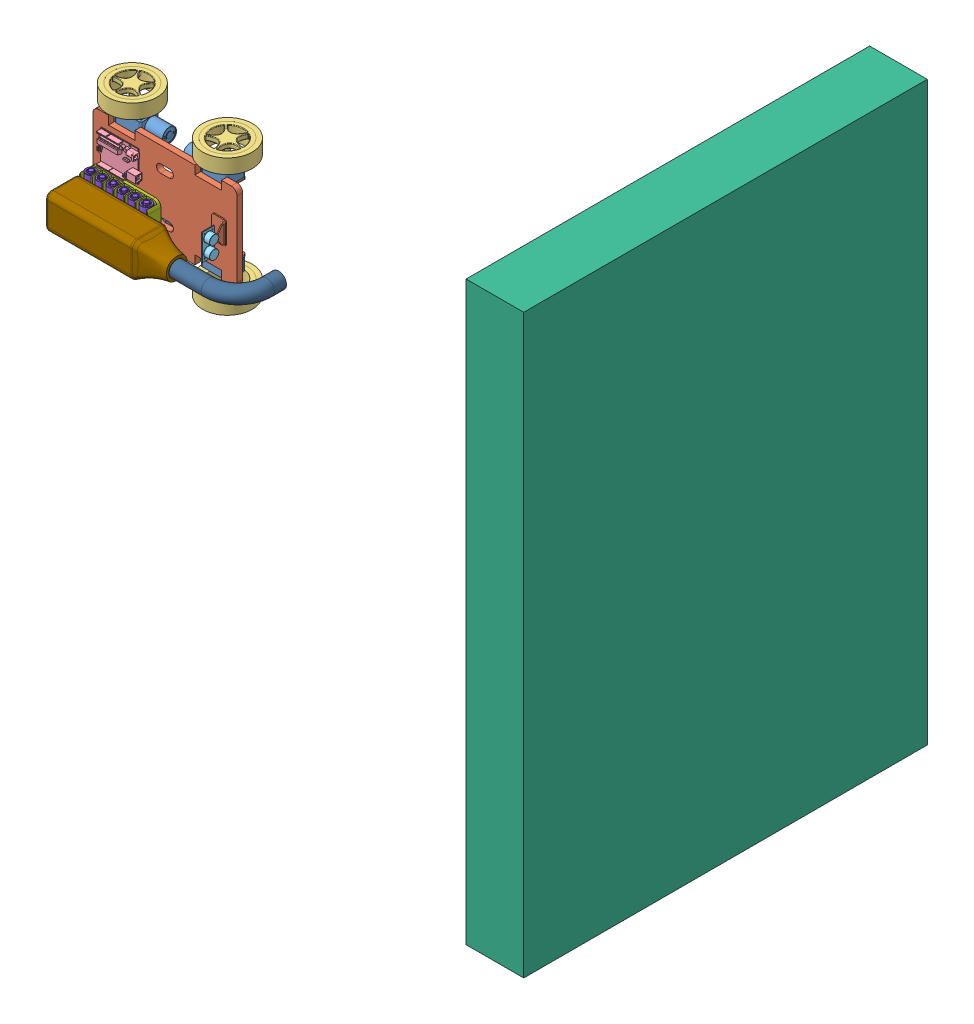
SolidWorks assembly Assem, configuration Default. Lengths in mm.
Overall size (1079.66 1000 700).
22 component instances, 10 part files, 36 mates.
Components (placement in the parent):
- 12v_DC_Gearmotor-1: 12v_DC_Gearmotor [Default] at (-163.6493 278.5619 69.9489) x (-1 0 0) z (0 0 1) size (79 38.4 32)
- Rover base-1: Rover base [Default] at (-238.6033 338.5619 90.9489) x (-1 0 0) z (0 0 1) size (250 150 80.5)
- 12v_DC_Gearmotor-2: 12v_DC_Gearmotor [Default] at (-163.6493 398.5619 69.9489) x (-1 0 0) z (0 0 -1) size (79 38.4 32)
- 12v_DC_Gearmotor-3: 12v_DC_Gearmotor [Default] at (-313.5573 278.5619 69.9489) x (1 0 0) z (0 0 -1) size (79 38.4 32)
- 12v_DC_Gearmotor-4: 12v_DC_Gearmotor [Default] at (-313.5573 398.5619 69.9489) size (79 38.4 32)
- Rover Tire-1: Rover Tire [Default] at (-321.0573 232.8619 69.9489) size (86 33.19 86)
- Rover Tire-3: Rover Tire [Default] at (-156.1493 232.8619 69.9489) size (86 33.19 86)
- Rover Tire-4: Rover Tire [Default] at (-156.1493 444.2619 69.9489) x (-0.973958 0 -0.22673) z (-0.22673 0 0.973958) size (86 33.19 86)
- Rover Tire-5: Rover Tire [Default] at (-321.0573 444.2619 69.9489) x (-0.837169 0 -0.546944) z (-0.546944 0 0.837169) size (86 33.19 86)
- arduino uno-1: arduino uno [Predeterminado] at (-316.1033 363.0619 95.9489) x (1 0 0) z (0 -1 0) size (74 12.5 53)
- ultrasonic sensor-1: ultrasonic sensor [Default] at (-131.8533 338.5619 127.9489) x (0 1 0) z (1 0 0) size (45.2 21 11.5)
- Wall-1: Wall [Default] at (649.0852 292.811 61.2372) x (0 0 1) z (-1 0 0) size (700 1000 100)
- Assem2-1: Assem2 [Default] at (-320.9073 237.9966 6.8256) size (118 67 23.02)
  - Battery Holder-1: Battery Holder [Default] at (16.304 59.0653 91.6233) size (118 67 23)
  - Lithium ion battery-1: Lithium ion battery [Default] at (-31.6544 58.0653 103.1233) size (18 66.5 18.02)
  - Lithium ion battery-2: Lithium ion battery [Default] at (64.3357 58.0653 103.1233) size (18 66.5 18.02)
  - Lithium ion battery-3: Lithium ion battery [Default] at (25.9042 58.0653 103.1233) size (18 66.5 18.02)
  - Lithium ion battery-4: Lithium ion battery [Default] at (6.6883 58.0653 103.1233) size (18 66.5 18.02)
  - Lithium ion battery-5: Lithium ion battery [Default] at (44.6923 58.0653 103.1233) size (18 66.5 18.02)
  - Lithium ion battery-6: Lithium ion battery [Default] at (-12.2228 58.0653 103.1233) size (18 66.5 18.02)
- vacuum bottle-1: vacuum bottle [Default] at (-288.6033 295.5619 148.9489) x (0 0 -1) z (1 0 0) size (60 60 218.62)
- vaccpipe-1: vaccpipe [Default] at (-164.9833 295.5619 148.9489) x (1 0 0) z (0 -1 0) size (119.32 84.35 27)
Mates (geometry in assembly coordinates):
- Coincident18: coincident anti-aligned: plane of 12v_DC_Gearmotor-1 through (-163.6493 278.5619 69.9489) normal (0 1 0); plane of Rover base-1 through (-140.6493 278.5619 85.9489) normal (0 -1 0)
- Coincident16: coincident anti-aligned: plane of 12v_DC_Gearmotor-1 through (-140.6493 257.0619 85.9489) normal (0 0 1); plane of Rover base-1 through (-238.6033 338.5619 85.9489) normal (0 0 -1)
- Coincident17: coincident aligned: plane of 12v_DC_Gearmotor-1 through (-140.6493 257.0619 85.9489) normal (1 0 0); plane of Rover base-1 through (-140.6493 283.5619 53.9489) normal (1 0 0)
- Coincident19: coincident aligned: plane of Rover base-1 through (-140.6493 393.5619 53.9489) normal (1 0 0); plane of 12v_DC_Gearmotor-2 through (-140.6493 420.0619 53.9489) normal (1 0 0)
- Coincident20: coincident anti-aligned: plane of Rover base-1 through (-140.6493 398.5619 85.9489) normal (0 1 0); plane of 12v_DC_Gearmotor-2 through (-163.6493 398.5619 69.9489) normal (0 -1 0)
- Coincident21: coincident anti-aligned: plane of Rover base-1 through (-238.6033 338.5619 85.9489) normal (0 0 -1); plane of 12v_DC_Gearmotor-2 through (-140.6493 420.0619 85.9489) normal (0 0 1)
- Coincident25: coincident anti-aligned: plane of Rover base-1 through (-336.5573 398.5619 85.9489) normal (0 1 0); plane of 12v_DC_Gearmotor-4 through (-313.5573 398.5619 69.9489) normal (0 -1 0)
- Coincident26: coincident aligned: plane of Rover base-1 through (-336.5573 393.5619 53.9489) normal (-1 0 0); plane of 12v_DC_Gearmotor-4 through (-336.5573 420.0619 85.9489) normal (-1 0 0)
- Coincident27: coincident anti-aligned: plane of Rover base-1 through (-238.6033 338.5619 85.9489) normal (0 0 -1); plane of 12v_DC_Gearmotor-4 through (-336.5573 420.0619 85.9489) normal (0 0 1)
- Coincident28: coincident anti-aligned: plane of Rover base-1 through (-336.5573 278.5619 85.9489) normal (0 -1 0); plane of 12v_DC_Gearmotor-3 through (-313.5573 278.5619 69.9489) normal (0 1 0)
- Coincident29: coincident aligned: plane of Rover base-1 through (-336.5573 283.5619 53.9489) normal (-1 0 0); plane of 12v_DC_Gearmotor-3 through (-336.5573 257.0619 53.9489) normal (-1 0 0)
- Coincident30: coincident anti-aligned: plane of Rover base-1 through (-238.6033 338.5619 85.9489) normal (0 0 -1); plane of 12v_DC_Gearmotor-3 through (-336.5573 257.0619 85.9489) normal (0 0 1)
- Concentric11: concentric aligned: line of 12v_DC_Gearmotor-4 through (-321.0573 433.7619 69.9489) axis (0 -1 0); cylinder of Rover Tire-5 through (-321.0573 433.7619 69.9489) axis (0 -1 0) radius 2.5
- Coincident31: coincident anti-aligned: plane of 12v_DC_Gearmotor-4 through (-321.0573 433.7619 69.9489) normal (0 1 0); plane of Rover Tire-5 through (-321.0573 433.7619 69.9489) normal (0 -1 0)
- Concentric2: concentric aligned: cylinder of 12v_DC_Gearmotor-2 through (-156.1493 433.7619 69.9489) axis (0 -1 0) radius 3; cylinder of Rover Tire-4 through (-156.1493 433.7619 69.9489) axis (0 -1 0) radius 2.5
- Coincident33: coincident anti-aligned: plane of 12v_DC_Gearmotor-2 through (-156.1493 433.7619 69.9489) normal (0 1 0); plane of Rover Tire-4 through (-156.1493 433.7619 69.9489) normal (0 -1 0)
- Concentric3: concentric aligned: cylinder of 12v_DC_Gearmotor-1 through (-156.1493 243.3619 69.9489) axis (0 1 0) radius 3; cylinder of Rover Tire-3 through (-156.1493 243.3619 69.9489) axis (0 1 0) radius 2.5
- Coincident34: coincident anti-aligned: plane of 12v_DC_Gearmotor-1 through (-156.1493 243.3619 69.9489) normal (0 -1 0); plane of Rover Tire-3 through (-156.1493 243.3619 69.9489) normal (0 1 0)
- Concentric4: concentric aligned: cylinder of 12v_DC_Gearmotor-3 through (-321.0573 243.3619 69.9489) axis (0 1 0) radius 3; cylinder of Rover Tire-1 through (-321.0573 243.3619 69.9489) axis (0 1 0) radius 2.5
- Coincident35: coincident anti-aligned: plane of 12v_DC_Gearmotor-3 through (-321.0573 243.3619 69.9489) normal (0 -1 0); plane of Rover Tire-1 through (-321.0573 243.3619 69.9489) normal (0 1 0)
- Concentric12: concentric aligned: cylinder of Rover base-1 through (-298.6033 338.5619 85.9489) axis (0 0 1) radius 2; cylinder of arduino uno-1 through (-298.6033 338.5619 95.9489) axis (0 0 1) radius 1.5
- Coincident39: coincident anti-aligned: plane of Rover base-1 through (-238.6033 338.5619 95.9489) normal (0 0 1); plane of arduino uno-1 through (-316.1033 363.0619 95.9489) normal (0 0 -1)
- Coincident40: coincident: point of Rover base-1; point of ultrasonic sensor-1
- Coincident41: coincident anti-aligned: plane of Rover base-1 through (-132.6033 323.5619 137.9489) normal (1 0 0); plane of ultrasonic sensor-1 through (-132.6033 338.5619 127.9489) normal (-1 0 0)
- Parallel2: parallel anti-aligned: plane of Rover base-1 through (-363.6033 338.5619 134.4489) normal (0 0 1); plane of ultrasonic sensor-1 through (-131.1033 315.9619 117.4489) normal (0 0 -1)
- Parallel4: parallel anti-aligned: plane of Rover base-1 through (-113.6033 263.5619 95.9489) normal (1 0 0); plane of Wall-1 through (599.0852 292.811 61.2372) normal (-1 0 0)
- LimitDistance1: limit distance = 712.6885 mm anti-aligned: plane of Rover base-1 through (-113.6033 263.5619 95.9489) normal (1 0 0); plane of Wall-1 through (599.0852 292.811 61.2372) normal (-1 0 0)
- Coincident42: coincident aligned: plane of Rover base-1 through (-363.6033 263.5619 95.9489) normal (-1 0 0); plane of Assem2-1/Battery Holder-1 through (-363.6033 297.0619 98.4489) normal (-1 0 0)
- Coincident43: coincident anti-aligned: plane of Rover base-1 through (-238.6033 338.5619 95.9489) normal (0 0 1); plane of Assem2-1/Battery Holder-1 through (-304.6033 297.0619 95.9489) normal (0 0 -1)
- Coincident44: coincident aligned: plane of Rover base-1 through (-113.6033 263.5619 95.9489) normal (0 -1 0); plane of Assem2-1/Battery Holder-1 through (-361.6033 263.5619 100.9489) normal (0 -1 0)
- Coincident45: coincident anti-aligned: plane of Assem2-1/Battery Holder-1 through (-228.6033 297.0619 118.9489) normal (0 0 1); plane of vacuum bottle-1 through (-213.6033 315.5619 118.9489) normal (0 0 -1)
- Coincident46: coincident aligned: plane of Assem2-1/Lithium ion battery-1 through (-352.5616 265.5619 109.9489) normal (0 -1 0); plane of vacuum bottle-1 through (-213.6033 265.5619 168.9489) normal (0 -1 0)
- Coincident47: coincident aligned: plane of Assem2-1/Battery Holder-1 through (-363.6033 297.0619 98.4489) normal (-1 0 0); plane of vacuum bottle-1 through (-363.6033 315.5619 128.9489) normal (-1 0 0)
- Concentric13: concentric anti-aligned: cylinder of vacuum bottle-1 through (-144.9833 295.5619 148.9489) axis (-1 0 0) radius 13; cylinder of vaccpipe-1 through (-169.9833 295.5619 148.9489) axis (1 0 0) radius 13.1
- Coincident49: coincident anti-aligned: plane of vacuum bottle-1 through (-164.9833 295.5619 166.9489) normal (1 0 0); plane of vaccpipe-1 through (-164.9833 295.5619 148.9489) normal (-1 0 0)
- Angle2: planar angle = 3.141593 rad anti-aligned: plane of vaccpipe-1 through (-59.1608 295.5619 78.0969) normal (0 0 -1); plane of Rover base-1 through (-238.6033 338.5619 85.9489) normal (0 0 -1)
